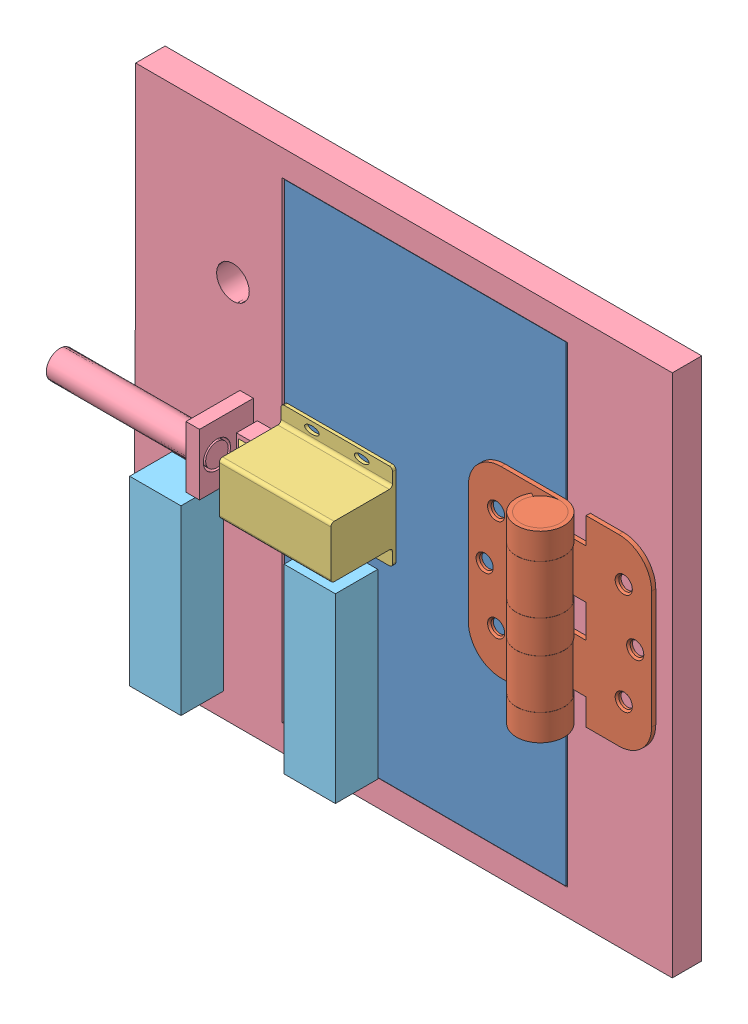
SolidWorks assembly door assembly, configuration Default. Lengths in mm.
Overall size (279.4 254.25 46.66).
5 component instances, 5 part files, 3 mates.
Components (placement in the parent):
- Door-1: Door [Default] at (137.2105 127.9564 140.1149) size (136.53 228.6 6.35)
- 1798A21_Surface-Mount_Hinge_with_Holes-2: 1798A21_Surface-Mount_Hinge_with_Holes [1798A21] at (201.8835 132.1759 157.6078) x (-1 0 0.000007) z (-0.000007 0 -1) size (88.9 88.9 23.11)
- Solenoid Lock-2: Solenoid Lock [Default] at (92.824 127.9564 147.2587) x (-1 0 0) z (0 0 -1) size (65.53 41.91 31.56)
- Door Frame-1: Door Frame [Default] at (134.1043 128.1152 144.2279) size (279.4 254.25 41.4)
- Safety_Sense-1: Safety_Sense [Default] at (120.254 58.3628 146.9803) size (99.82 88.65 20.57)
Mates (geometry in assembly coordinates):
- Coincident9: coincident anti-aligned: plane of Door-1 through (65.773 13.6564 145.6712) normal (0 0 1); plane of Solenoid Lock-2 through (92.824 127.9564 145.6712) normal (0 0 -1)
- Coincident10: coincident aligned: line of Door-1 through (65.773 13.6564 145.6712) axis (0 1 0); line of Solenoid Lock-2 through (65.773 108.5889 145.6712) axis (0 1 0)
- Coincident12: coincident: point of Door-1; unknown of Solenoid Lock-2
